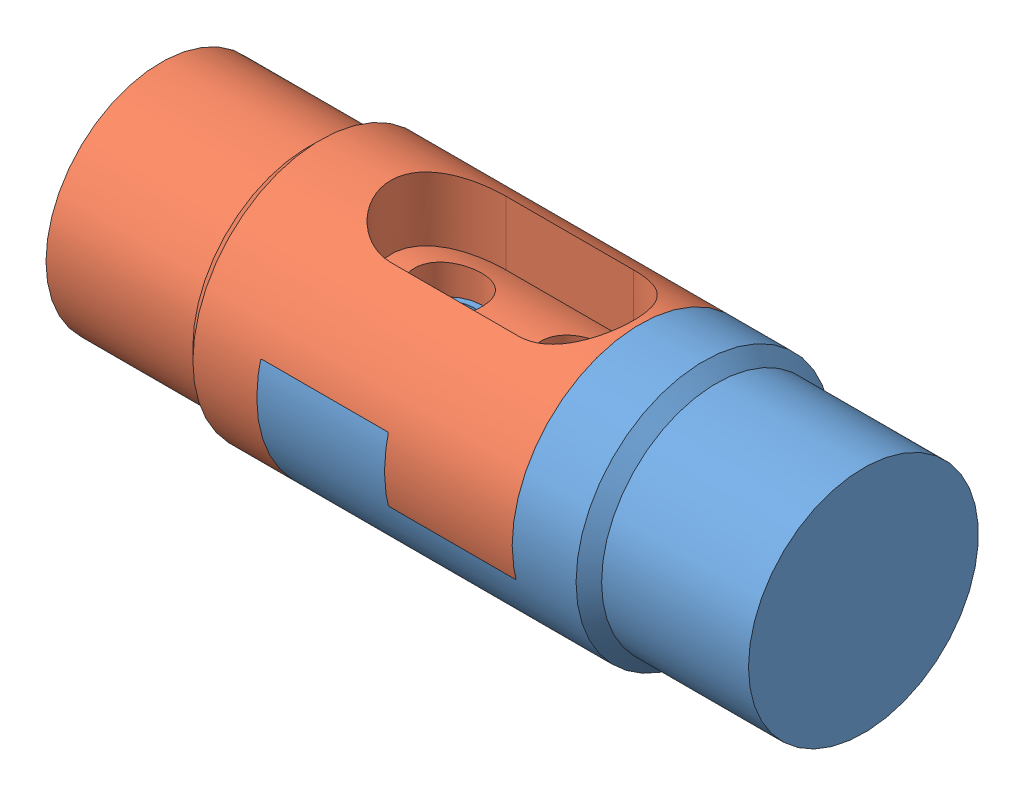
SolidWorks assembly Assemblage1, configuration Défaut. Lengths in mm.
Overall size (110 40.01 40).
2 component instances, 2 part files, 3 mates.
Components (placement in the parent):
- Tube interlocking -2: Tube interlocking  [Défaut] at (86.9081 5.9422 75) size (75 40 40)
- Tube interlocking  2-3: Tube interlocking  2 [Défaut] at (-66.5331 -15.0656 75) x (-1 0 0) z (0 0 1) size (75 40.01 40)
Mates (geometry in assembly coordinates):
- Verrouiller1: lock: unknown of Tube interlocking -2
- Distance1: distance = 0 mm: line of Tube interlocking  2-3 through (10.3875 -9.5617 94.3649) axis (1 0 0); line of Tube interlocking -2 through (29.9875 -9.5617 94.3649) axis (-1 0 0)
- Coïncidente1: coincident aligned: circle of Tube interlocking -2; circle of Tube interlocking  2-3
